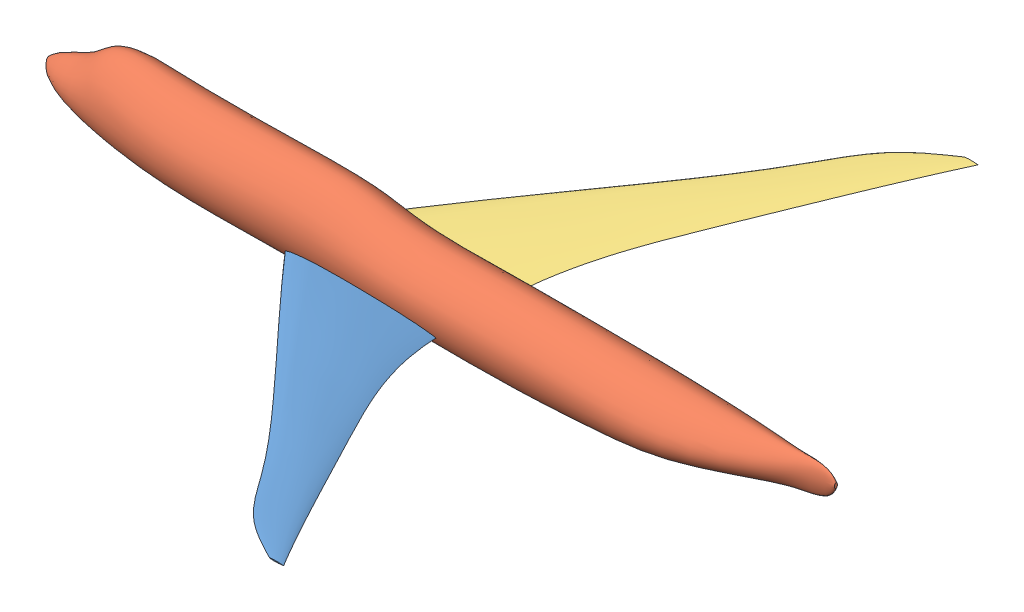
SolidWorks assembly Assem2, configuration Default. Lengths in mm.
Overall size (264.87 30.68 230.7).
3 component instances, 3 part files, 3 mates.
Components (placement in the parent):
- b747-8-left-wing-1: b747-8-left-wing [Default] at origin size (106.65 17.13 107.36)
- fuselage-1: fuselage [Default] at (-87.376 -2 -8) size (264.87 30.68 24.71)
- Mirrorb747-8-left-wing-2: Mirrorb747-8-left-wing [Default] at (0 0 -16) size (106.65 17.13 107.36)
Mates (geometry in assembly coordinates):
- Coincident1: coincident: plane of fuselage-1 through (-87.376 -2 0) normal (0 0 1); plane of b747-8-left-wing-1 through (0 0 0) normal (0 0 1)
- Coincident2: coincident: plane of b747-8-left-wing-1 through (0 0 0) normal (0 1 0); plane of fuselage-1 through (-87.376 0 -8) normal (0 1 0)
- Coincident3: coincident: plane of b747-8-left-wing-1 through (0 0 0) normal (1 0 0); plane of fuselage-1 through (0 -2 -8) normal (1 0 0)
